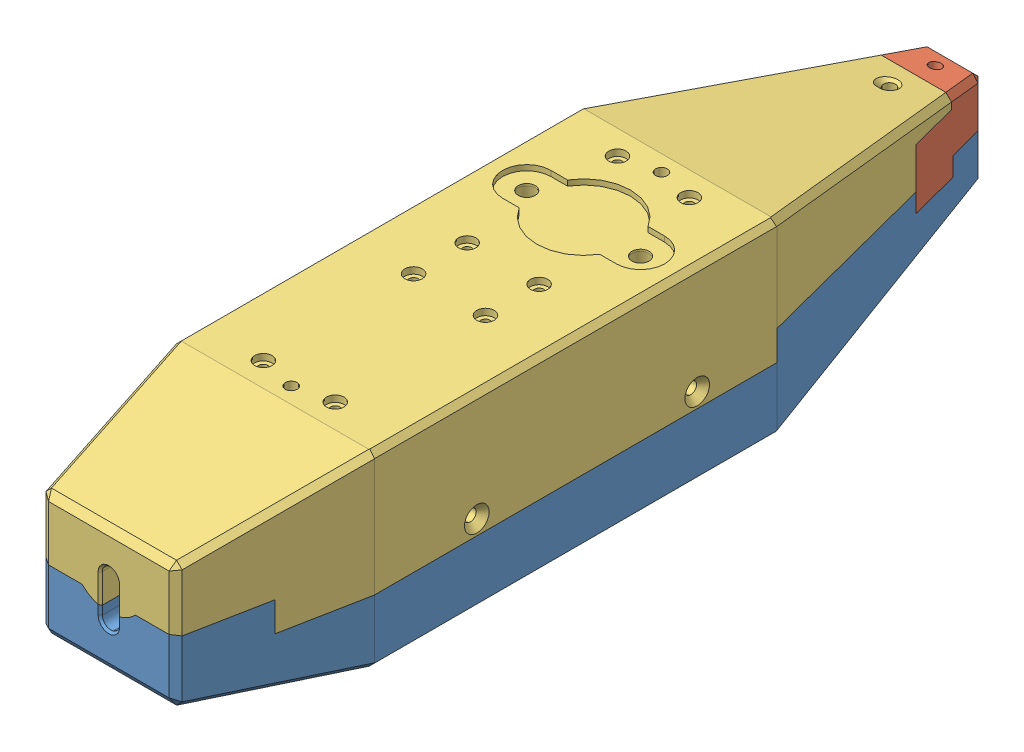
SolidWorks assembly CasingAssembly, configuration Default. Lengths in mm.
Overall size (37 35 158).
3 component instances, 3 part files, 6 mates.
Components (placement in the parent):
- Body2-1: Body2 [Default] at origin size (37 17.5 158)
- Body1-2: Body1 [Default] at origin size (18.83 13.38 17)
- Body3-1: Body3 [Default] at origin size (37 23 150)
Mates (geometry in assembly coordinates):
- Coincident1: coincident anti-aligned: plane of Body2-1 through (15.5 0 68.5) normal (1 0 0); plane of Body3-1 through (15.5 0 68.5) normal (-1 0 0)
- Coincident2: coincident anti-aligned: plane of Body2-1 through (0 -5.5 68.5) normal (0 1 0); plane of Body3-1 through (0 -5.5 68.5) normal (0 -1 0)
- Coincident3: coincident anti-aligned: plane of Body2-1 through (7 -3.5 -89.5) normal (1 0 0); plane of Body1-2 through (7 -3.5 -89.5) normal (-1 0 0)
- Coincident4: coincident anti-aligned: plane of Body2-1 through (10 -3.5 -89.5) normal (0 1 0); plane of Body1-2 through (10 -3.5 -89.5) normal (0 -1 0)
- LimitDistance1: limit distance = 0 mm anti-aligned: plane of Body3-1 through (0 0 -37.5) normal (0 0 -1); plane of Body2-1 through (0 0 -37.5) normal (0 0 1)
- LimitDistance2: limit distance = 0 mm anti-aligned: plane of Body1-2 through (8.334 288600.2888 -72.5) normal (0 0 1); plane of Body2-1 through (0 -3.5 -72.5) normal (0 0 -1)
